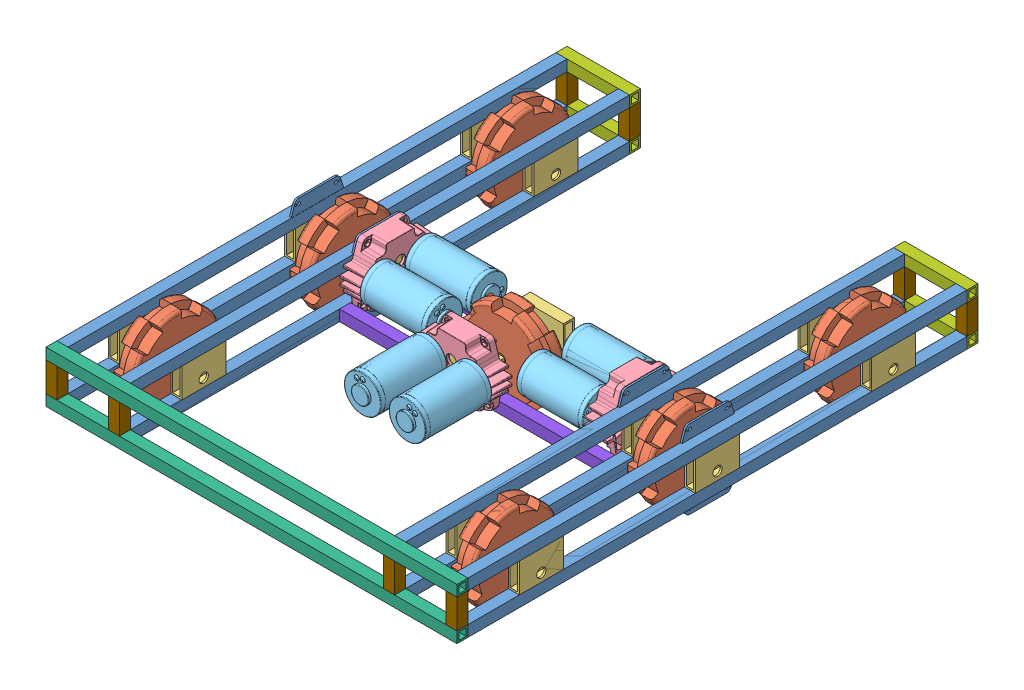
SolidWorks assembly Drive train Assem, configuration Default. Lengths in mm.
Overall size (711.2 207.75 901.7).
102 component instances, 9 part files, 40 mates.
Components (placement in the parent):
- Rod(38)-1: Rod(38) [Default] at (232.2427 460.842 1135.3317) size (19.05 42.61 863.6)
- Rod(38)-2: Rod(38) [Default] at (124.2927 460.842 1135.3317) size (19.05 42.61 863.6)
- Rod(38)-7: Rod(38) [Default] at (232.2427 390.992 271.7317) x (1 0 0) z (0 0 -1) size (19.05 42.61 863.6)
- Rod(38)-8: Rod(38) [Default] at (124.2927 390.992 271.7317) x (1 0 0) z (0 0 -1) size (19.05 42.61 863.6)
- Omni_Wheel_Six_Inch-1: Omni_Wheel_Six_Inch [Default] at (159.2177 414.8679 703.5318) x (1 0 0) z (0 0.491398 -0.870935) size (38.39 152.46 152.55)
- Wheel_Holder-1: Wheel_Holder [Default] at (232.2427 425.917 741.6317) size (19.05 50.8 76.2)
- Wheel_Holder-2: Wheel_Holder [Default] at (124.2927 425.917 665.4317) x (-1 0 0) z (0 0 -1) size (19.05 50.8 76.2)
- Wheel_Holder-5: Wheel_Holder [Default] at (124.2927 425.917 360.6317) x (-1 0 0) z (0 0 -1) size (19.05 50.8 76.2)
- Wheel_Holder-6: Wheel_Holder [Default] at (124.2927 425.917 970.2317) x (-1 0 0) z (0 0 -1) size (19.05 50.8 76.2)
- Wheel_Holder-7: Wheel_Holder [Default] at (124.2927 425.917 665.4317) x (-1 0 0) z (0 0 -1) size (19.05 50.8 76.2)
- Omni_Wheel_Six_Inch-3: Omni_Wheel_Six_Inch [Default] at (159.2177 414.8679 398.7318) x (1 0 0) z (0 0.491398 -0.870935) size (38.39 152.46 152.55)
- Omni_Wheel_Six_Inch-4: Omni_Wheel_Six_Inch [Default] at (159.2177 414.8679 1008.3318) x (1 0 0) z (0 0.491398 -0.870935) size (38.39 152.46 152.55)
- Omni_Wheel_Six_Inch-5: Omni_Wheel_Six_Inch [Default] at (159.2177 414.8679 703.5318) x (1 0 0) z (0 0.491398 -0.870935) size (38.39 152.46 152.55)
- Wheel_Holder-8: Wheel_Holder [Default] at (232.2427 425.917 436.8317) size (19.05 50.8 76.2)
- Wheel_Holder-9: Wheel_Holder [Default] at (232.2427 425.917 1046.4317) size (19.05 50.8 76.2)
- Wheel_Holder-10: Wheel_Holder [Default] at (232.2427 425.917 741.6317) size (19.05 50.8 76.2)
- TM_Housing-1: TM_Housing [Default] at (78.9537 414.868 703.5317) x (0 0 -1) z (1 0 0) size (139.9 118.55 41.53)
- CIM_Motor-1: CIM_Motor [Default] at (59.9037 530.8918 668.1595) x (0 0.376645 0.926357) z (1 0 0) size (64.01 64.01 154.94)
- CIM_Motor-2: CIM_Motor [Default] at (59.9037 328.3971 656.572) x (0 0.376645 -0.926357) z (1 0 0) size (64.01 64.01 154.94)
- Wheel_Holder-11: Wheel_Holder [Default] at (-459.9073 425.917 970.2317) x (-1 0 0) z (0 0 -1) size (19.05 50.8 76.2)
- Omni_Wheel_Six_Inch-6: Omni_Wheel_Six_Inch [Default] at (-425.2716 414.8679 703.5318) x (1 0 0) z (0 0.491398 -0.870935) size (38.39 152.46 152.55)
- Wheel_Holder-12: Wheel_Holder [Default] at (-351.9573 425.917 741.6317) size (19.05 50.8 76.2)
- Omni_Wheel_Six_Inch-7: Omni_Wheel_Six_Inch [Default] at (-425.2716 414.8679 703.5318) x (1 0 0) z (0 0.491398 -0.870935) size (38.39 152.46 152.55)
- Wheel_Holder-13: Wheel_Holder [Default] at (-351.9573 425.917 741.6317) size (19.05 50.8 76.2)
- TM_Housing-2: TM_Housing [Default] at (-306.6183 414.868 703.5317) x (0 0 1) z (-1 0 0) size (139.9 118.55 41.53)
- Omni_Wheel_Six_Inch-8: Omni_Wheel_Six_Inch [Default] at (-425.2716 414.8679 1008.3318) x (1 0 0) z (0 0.491398 -0.870935) size (38.39 152.46 152.55)
- Wheel_Holder-14: Wheel_Holder [Default] at (-351.9573 425.917 1046.4317) size (19.05 50.8 76.2)
- Wheel_Holder-15: Wheel_Holder [Default] at (-459.9073 425.917 360.6317) x (-1 0 0) z (0 0 -1) size (19.05 50.8 76.2)
- Omni_Wheel_Six_Inch-9: Omni_Wheel_Six_Inch [Default] at (-425.2716 414.8679 398.7318) x (1 0 0) z (0 0.491398 -0.870935) size (38.39 152.46 152.55)
- Wheel_Holder-16: Wheel_Holder [Default] at (-459.9073 425.917 665.4317) x (-1 0 0) z (0 0 -1) size (19.05 50.8 76.2)
- Rod(38)-9: Rod(38) [Default] at (-459.9073 460.842 271.7317) x (-1 0 0) z (0 0 -1) size (19.05 42.61 863.6)
- Rod(38)-10: Rod(38) [Default] at (-351.9573 390.992 1135.3317) x (-1 0 0) z (0 0 1) size (19.05 42.61 863.6)
- Rod(38)-11: Rod(38) [Default] at (-459.9073 390.992 1135.3317) x (-1 0 0) z (0 0 1) size (19.05 42.61 863.6)
- Rod(38)-12: Rod(38) [Default] at (-351.9573 460.842 271.7317) x (-1 0 0) z (0 0 -1) size (19.05 42.61 863.6)
- CIM_Motor-3: CIM_Motor [Default] at (-287.5683 328.3971 750.4913) x (0 0.376645 0.926357) z (-1 0 0) size (64.01 64.01 154.94)
- CIM_Motor-4: CIM_Motor [Default] at (-287.5683 530.8918 738.9039) x (0 0.376645 -0.926357) z (-1 0 0) size (64.01 64.01 154.94)
- Wheel_Holder-17: Wheel_Holder [Default] at (-351.9573 425.917 436.8317) size (19.05 50.8 76.2)
- Wheel_Holder-18: Wheel_Holder [Default] at (-459.9073 425.917 665.4317) x (-1 0 0) z (0 0 -1) size (19.05 50.8 76.2)
- Rod(28)-1: Rod(28) [Default] at (241.7677 460.842 1144.8567) x (0 0 -1) z (1 0 0) size (19.05 19.05 711.2)
- Rod(28)-2: Rod(28) [Default] at (-469.4323 390.992 1144.8567) x (0 0 -1) z (-1 0 0) size (19.05 19.05 711.2)
- Rod(5)-1: Rod(5) [Default] at (114.7677 460.842 262.2067) x (0 0 1) z (-1 0 0) size (19.05 19.05 127)
- Rod(5)-2: Rod(5) [Default] at (241.7677 390.992 262.2067) x (0 0 1) z (1 0 0) size (19.05 19.05 127)
- Rod(5)-3: Rod(5) [Default] at (-469.4323 460.842 262.2067) x (0 0 1) z (-1 0 0) size (19.05 19.05 127)
- Rod(5)-4: Rod(5) [Default] at (-342.4323 390.992 262.2067) x (0 0 1) z (1 0 0) size (19.05 19.05 127)
- Rod(18)-1: Rod(18) [Default] at (114.7677 390.992 643.2067) x (0 0 -1) z (1 0 0) size (19.05 19.05 457.2)
- Wheel_Holder-19: Wheel_Holder [Default] at (-151.9323 425.917 643.2067) x (0 0 1) z (-1 0 0) size (19.05 50.8 76.2)
- Wheel_Holder-20: Wheel_Holder [Default] at (-75.7323 425.917 763.8567) x (0 0 -1) z (1 0 0) size (19.05 50.8 76.2)
- Rod(18)-2: Rod(18) [Default] at (-342.4323 390.992 763.8567) x (0 0 1) z (-1 0 0) size (19.05 19.05 457.2)
- Omni_Wheel_Six_Inch-10: Omni_Wheel_Six_Inch [Default] at (-113.8323 414.868 722.5817) x (0 0 -1) z (0.155594 -0.987821 0) size (38.39 152.46 152.55)
- TM_Housing-3: TM_Housing [Default] at (-113.8323 414.868 809.1957) x (-0.99996 0.008991 0) z (0 0 -1) size (139.9 118.55 41.53)
- CIM_Motor-5: CIM_Motor [Default] at (-164.6523 370.9605 828.2457) x (-0.351705 0.936111 0) z (0 0 -1) size (64.01 64.01 154.94)
- CIM_Motor-6: CIM_Motor [Default] at (-180.7617 332.0262 828.2457) x (-0.844762 0.535142 0) z (0 0 -1) size (64.01 64.01 154.94)
- Rod(2)-1: Rod(2) [Default] at (124.2927 451.317 262.2067) x (1 0 0) z (0 1 0) size (19.05 19.05 50.8)
- Rod(2)-2: Rod(2) [Default] at (124.2927 400.517 1144.8567) x (1 0 0) z (0 -1 0) size (19.05 19.05 50.8)
- Rod(2)-3: Rod(2) [Default] at (232.2427 451.317 1144.8567) x (-1 0 0) z (0 1 0) size (19.05 19.05 50.8)
- Rod(2)-4: Rod(2) [Default] at (232.2427 400.517 262.2067) x (-1 0 0) z (0 -1 0) size (19.05 19.05 50.8)
- Rod(2)-5: Rod(2) [Default] at (-351.9573 400.517 262.2067) x (-1 0 0) z (0 -1 0) size (19.05 19.05 50.8)
- Wheel_Holder-21: Wheel_Holder [Default] at (-459.9073 425.917 970.2317) x (-1 0 0) z (0 0 -1) size (19.05 50.8 76.2)
- Omni_Wheel_Six_Inch-11: Omni_Wheel_Six_Inch [Default] at (-425.2716 414.8679 703.5318) x (1 0 0) z (0 0.491398 -0.870935) size (38.39 152.46 152.55)
- Wheel_Holder-22: Wheel_Holder [Default] at (-351.9573 425.917 741.6317) size (19.05 50.8 76.2)
- Omni_Wheel_Six_Inch-12: Omni_Wheel_Six_Inch [Default] at (-425.2716 414.8679 703.5318) x (1 0 0) z (0 0.491398 -0.870935) size (38.39 152.46 152.55)
- Wheel_Holder-23: Wheel_Holder [Default] at (-351.9573 425.917 741.6317) size (19.05 50.8 76.2)
- TM_Housing-4: TM_Housing [Default] at (-306.6183 414.868 703.5317) x (0 0 1) z (-1 0 0) size (139.9 118.55 41.53)
- Omni_Wheel_Six_Inch-13: Omni_Wheel_Six_Inch [Default] at (-425.2716 414.8679 1008.3318) x (1 0 0) z (0 0.491398 -0.870935) size (38.39 152.46 152.55)
- Wheel_Holder-24: Wheel_Holder [Default] at (-351.9573 425.917 1046.4317) size (19.05 50.8 76.2)
- Wheel_Holder-25: Wheel_Holder [Default] at (-459.9073 425.917 360.6317) x (-1 0 0) z (0 0 -1) size (19.05 50.8 76.2)
- Omni_Wheel_Six_Inch-14: Omni_Wheel_Six_Inch [Default] at (-425.2716 414.8679 398.7318) x (1 0 0) z (0 0.491398 -0.870935) size (38.39 152.46 152.55)
- Wheel_Holder-26: Wheel_Holder [Default] at (-459.9073 425.917 665.4317) x (-1 0 0) z (0 0 -1) size (19.05 50.8 76.2)
- Rod(38)-13: Rod(38) [Default] at (-459.9073 460.842 271.7317) x (-1 0 0) z (0 0 -1) size (19.05 42.61 863.6)
- Rod(38)-14: Rod(38) [Default] at (-351.9573 390.992 1135.3317) x (-1 0 0) z (0 0 1) size (19.05 42.61 863.6)
- Rod(38)-15: Rod(38) [Default] at (-459.9073 390.992 1135.3317) x (-1 0 0) z (0 0 1) size (19.05 42.61 863.6)
- Rod(38)-16: Rod(38) [Default] at (-351.9573 460.842 271.7317) x (-1 0 0) z (0 0 -1) size (19.05 42.61 863.6)
- CIM_Motor-7: CIM_Motor [Default] at (-287.5683 328.3971 750.4913) x (0 0.376645 0.926357) z (-1 0 0) size (64.01 64.01 154.94)
- CIM_Motor-8: CIM_Motor [Default] at (-287.5683 530.8918 738.9039) x (0 0.376645 -0.926357) z (-1 0 0) size (64.01 64.01 154.94)
- Wheel_Holder-27: Wheel_Holder [Default] at (-351.9573 425.917 436.8317) size (19.05 50.8 76.2)
- Wheel_Holder-28: Wheel_Holder [Default] at (-459.9073 425.917 665.4317) x (-1 0 0) z (0 0 -1) size (19.05 50.8 76.2)
- Rod(5)-5: Rod(5) [Default] at (-469.4323 460.842 262.2067) x (0 0 1) z (-1 0 0) size (19.05 19.05 127)
- Rod(2)-6: Rod(2) [Default] at (-351.9573 400.517 262.2067) x (-1 0 0) z (0 -1 0) size (19.05 19.05 50.8)
- Wheel_Holder-29: Wheel_Holder [Default] at (232.2427 425.917 1046.4317) size (19.05 50.8 76.2)
- Omni_Wheel_Six_Inch-15: Omni_Wheel_Six_Inch [Default] at (159.2177 414.8679 703.5318) x (1 0 0) z (0 0.491398 -0.870935) size (38.39 152.46 152.55)
- Wheel_Holder-30: Wheel_Holder [Default] at (124.2927 425.917 665.4317) x (-1 0 0) z (0 0 -1) size (19.05 50.8 76.2)
- Omni_Wheel_Six_Inch-16: Omni_Wheel_Six_Inch [Default] at (159.2177 414.8679 703.5318) x (1 0 0) z (0 0.491398 -0.870935) size (38.39 152.46 152.55)
- Wheel_Holder-31: Wheel_Holder [Default] at (124.2927 425.917 665.4317) x (-1 0 0) z (0 0 -1) size (19.05 50.8 76.2)
- TM_Housing-5: TM_Housing [Default] at (78.9537 414.868 703.5317) x (0 0 -1) z (1 0 0) size (139.9 118.55 41.53)
- Omni_Wheel_Six_Inch-17: Omni_Wheel_Six_Inch [Default] at (159.2177 414.8679 1008.3318) x (1 0 0) z (0 0.491398 -0.870935) size (38.39 152.46 152.55)
- Wheel_Holder-32: Wheel_Holder [Default] at (124.2927 425.917 970.2317) x (-1 0 0) z (0 0 -1) size (19.05 50.8 76.2)
- Wheel_Holder-33: Wheel_Holder [Default] at (232.2427 425.917 436.8317) size (19.05 50.8 76.2)
- Omni_Wheel_Six_Inch-18: Omni_Wheel_Six_Inch [Default] at (159.2177 414.8679 398.7318) x (1 0 0) z (0 0.491398 -0.870935) size (38.39 152.46 152.55)
- Wheel_Holder-34: Wheel_Holder [Default] at (232.2427 425.917 741.6317) size (19.05 50.8 76.2)
- Rod(38)-17: Rod(38) [Default] at (232.2427 460.842 1135.3317) size (19.05 42.61 863.6)
- Rod(38)-18: Rod(38) [Default] at (124.2927 390.992 271.7317) x (1 0 0) z (0 0 -1) size (19.05 42.61 863.6)
- Rod(38)-19: Rod(38) [Default] at (232.2427 390.992 271.7317) x (1 0 0) z (0 0 -1) size (19.05 42.61 863.6)
- Rod(38)-20: Rod(38) [Default] at (124.2927 460.842 1135.3317) size (19.05 42.61 863.6)
- CIM_Motor-9: CIM_Motor [Default] at (59.9037 530.8918 668.1595) x (0 0.376645 0.926357) z (1 0 0) size (64.01 64.01 154.94)
- CIM_Motor-10: CIM_Motor [Default] at (59.9037 328.3971 656.572) x (0 0.376645 -0.926357) z (1 0 0) size (64.01 64.01 154.94)
- Wheel_Holder-35: Wheel_Holder [Default] at (124.2927 425.917 360.6317) x (-1 0 0) z (0 0 -1) size (19.05 50.8 76.2)
- Wheel_Holder-36: Wheel_Holder [Default] at (232.2427 425.917 741.6317) size (19.05 50.8 76.2)
- Rod(5)-6: Rod(5) [Default] at (114.7677 460.842 262.2067) x (0 0 1) z (-1 0 0) size (19.05 19.05 127)
- Rod(2)-7: Rod(2) [Default] at (124.2927 451.317 262.2067) x (1 0 0) z (0 1 0) size (19.05 19.05 50.8)
- Rod(2)-8: Rod(2) [Default] at (-351.9573 451.317 1144.8567) x (-1 0 0) z (0 1 0) size (19.05 19.05 50.8)
- Rod(2)-9: Rod(2) [Default] at (-459.9073 400.517 1144.8567) x (1 0 0) z (0 -1 0) size (19.05 19.05 50.8)
- Rod(2)-10: Rod(2) [Default] at (-459.9073 451.317 262.2067) x (1 0 0) z (0 1 0) size (19.05 19.05 50.8)
Mates (geometry in assembly coordinates):
- Parallel1: parallel aligned: plane of Rod(38)-1 through (222.7177 470.367 271.7317) normal (0 1 0); plane of Rod(38)-2 through (114.7677 470.367 271.7317) normal (0 1 0)
- Parallel2: parallel aligned: plane of Rod(38)-1 through (241.7677 451.317 271.7317) normal (1 0 0); plane of Rod(38)-2 through (133.8177 451.317 271.7317) normal (1 0 0)
- Coincident3: coincident aligned: plane of Rod(38)-1 through (222.7177 451.317 271.7317) normal (0 -1 0); plane of Rod(38)-2 through (114.7677 451.317 271.7317) normal (0 -1 0)
- Coincident4: coincident aligned: plane of Rod(38)-1 through (232.2427 460.842 271.7317) normal (0 0 -1); plane of Rod(38)-2 through (124.2927 460.842 271.7317) normal (0 0 -1)
- Parallel3: parallel anti-aligned: plane of Rod(38)-1 through (222.7177 451.317 271.7317) normal (-1 0 0); plane of Omni_Wheel_Six_Inch-1 through (197.3177 414.8679 703.5318) normal (1 0 0)
- Distance3: distance = 88.9 mm anti-aligned: plane of Rod(38)-1 through (222.7177 451.317 271.7317) normal (-1 0 0); plane of Rod(38)-2 through (133.8177 451.317 271.7317) normal (1 0 0)
- Coincident9: coincident anti-aligned: plane of Omni_Wheel_Six_Inch-1 through (178.2677 414.8679 703.5318) normal (-1 0 0)
- Coincident10: coincident anti-aligned: plane of Rod(38)-7 through (222.7177 400.517 1135.3317) normal (0 1 0); plane of Wheel_Holder-1 through (222.7177 400.517 665.4317) normal (0 -1 0)
- Coincident12: coincident anti-aligned: plane of Rod(38)-7 through (222.7177 400.517 1135.3317) normal (0 1 0); plane of Wheel_Holder-1 through (222.7177 400.517 665.4317) normal (0 -1 0)
- Coincident13: coincident aligned: plane of Rod(38)-7 through (241.7677 400.517 1135.3317) normal (1 0 0); plane of Wheel_Holder-1 through (241.7677 400.517 665.4317) normal (1 0 0)
- Concentric1: concentric aligned: circle of Omni_Wheel_Six_Inch-1; circle of Wheel_Holder-1
- Symmetric1: symmetric aligned: plane of Wheel_Holder-1 through (232.2427 425.917 741.6317) normal (0 0 1); plane of Wheel_Holder-1 through (232.2427 425.917 665.4317) normal (0 0 -1)
- Coincident14: coincident anti-aligned: plane of Rod(38)-2 through (114.7677 451.317 271.7317) normal (-1 0 0); plane of TM_Housing-1 through (114.7677 414.868 703.5317) normal (1 0 0)
- Concentric2: concentric anti-aligned: cylinder of Wheel_Holder-7 through (133.8177 414.868 703.5317) axis (-1 0 0) radius 8.001; cylinder of TM_Housing-1 through (114.7677 414.868 703.5317) axis (1 0 0) radius 5.08
- Concentric3: concentric anti-aligned: cylinder of Rod(38)-2 through (117.9427 485.456 671.7817) axis (-1 0 0) radius 2.5576; cone of TM_Housing-1 through (109.416 485.456 671.7817) axis (1 0 0)
- Coincident15: coincident anti-aligned: plane of TM_Housing-1 through (78.9537 414.868 703.5317) normal (-1 0 0); plane of CIM_Motor-1 through (78.9537 443.038 742.2667) normal (1 0 0)
- Concentric4: concentric anti-aligned: cylinder of TM_Housing-1 through (114.7677 443.038 742.2667) axis (1 0 0) radius 10.414; cylinder of CIM_Motor-1 through (114.5177 443.038 742.2667) axis (-1 0 0) radius 4
- Coincident16: coincident anti-aligned: plane of Rod(38)-9 through (-459.9073 460.842 1135.3317) normal (0 0 1); plane of Rod(28)-1 through (-469.4323 451.317 1135.3317) normal (0 0 -1)
- Coincident17: coincident aligned: plane of Rod(38)-1 through (241.7677 451.317 271.7317) normal (1 0 0); plane of Rod(28)-1 through (241.7677 460.842 1144.8567) normal (1 0 0)
- Coincident18: coincident aligned: plane of Rod(38)-1 through (222.7177 451.317 271.7317) normal (0 -1 0); plane of Rod(28)-1 through (-469.4323 451.317 1154.3817) normal (0 -1 0)
- Coincident19: coincident anti-aligned: plane of Rod(38)-2 through (124.2927 460.842 271.7317) normal (0 0 -1); plane of Rod(5)-1 through (241.7677 451.317 271.7317) normal (0 0 1)
- Coincident20: coincident aligned: plane of Rod(38)-1 through (241.7677 451.317 271.7317) normal (1 0 0); plane of Rod(5)-1 through (241.7677 460.842 262.2067) normal (1 0 0)
- Coincident21: coincident aligned: plane of Rod(38)-2 through (114.7677 470.367 271.7317) normal (0 1 0); plane of Rod(5)-1 through (241.7677 470.367 252.6817) normal (0 1 0)
- Coincident22: coincident anti-aligned: plane of Rod(38)-10 through (-342.4323 400.517 271.7317) normal (1 0 0); plane of Rod(18)-1 through (-342.4323 390.992 643.2067) normal (-1 0 0)
- Coincident23: coincident aligned: plane of Rod(38)-10 through (-342.4323 400.517 271.7317) normal (0 1 0); plane of Rod(18)-1 through (-342.4323 400.517 652.7317) normal (0 1 0)
- Distance4: distance = 50.8 mm: plane of assembly through (0 0 703.5317) normal (0 0 1); plane of Rod(18)-1 through (-342.4323 381.467 652.7317) normal (0 0 1)
- Coincident24: coincident anti-aligned: plane of Rod(18)-1 through (-342.4323 400.517 652.7317) normal (0 1 0); plane of Wheel_Holder-19 through (-75.7323 400.517 633.6817) normal (0 -1 0)
- Coincident27: coincident aligned: plane of Rod(18)-1 through (-342.4323 381.467 652.7317) normal (0 0 1); plane of Wheel_Holder-19 through (-75.7323 400.517 652.7317) normal (0 0 1)
- Symmetric2: symmetric aligned: plane of Wheel_Holder-19 through (-75.7323 425.917 643.2067) normal (1 0 0); plane of Wheel_Holder-19 through (-151.9323 425.917 643.2067) normal (-1 0 0)
- Coincident28: coincident anti-aligned: plane of Omni_Wheel_Six_Inch-10 through (-113.8323 414.868 703.5317) normal (0 0 -1)
- Concentric5: concentric aligned: cylinder of Wheel_Holder-19 through (-113.8323 414.868 633.6817) axis (0 0 1) radius 8.001; cylinder of Omni_Wheel_Six_Inch-10 through (-113.8323 414.868 684.4817) axis (0 0 1) radius 7.9375
- Coincident30: coincident anti-aligned: plane of Wheel_Holder-20 through (-151.9323 400.517 773.3817) normal (0 0 1); plane of TM_Housing-3 through (-113.8323 414.868 773.3817) normal (0 0 -1)
- Concentric6: concentric aligned: cylinder of Wheel_Holder-20 through (-113.8323 414.868 773.3817) axis (0 0 -1) radius 8.001; cylinder of TM_Housing-3 through (-113.8323 414.868 773.3817) axis (0 0 -1) radius 5.08
- Coincident34: coincident anti-aligned: plane of TM_Housing-3 through (-113.8323 414.868 809.1957) normal (0 0 1); plane of CIM_Motor-5 through (-74.8456 442.6886 809.1957) normal (0 0 -1)
- Concentric7: concentric anti-aligned: cylinder of TM_Housing-3 through (-74.8456 442.6886 773.3817) axis (0 0 -1) radius 10.414; cylinder of CIM_Motor-5 through (-74.8456 442.6886 773.6317) axis (0 0 1) radius 4
- Coincident35: coincident anti-aligned: plane of TM_Housing-3 through (-113.8323 414.868 809.1957) normal (0 0 1); plane of CIM_Motor-6 through (-152.3124 443.3851 809.1957) normal (0 0 -1)
- Concentric8: concentric anti-aligned: cylinder of TM_Housing-3 through (-152.3124 443.3851 773.3817) axis (0 0 -1) radius 10.414; cylinder of CIM_Motor-6 through (-152.3124 443.3851 773.6317) axis (0 0 1) radius 4
- Coincident36: coincident anti-aligned: plane of Rod(5)-2 through (114.7677 400.517 252.6817) normal (0 1 0); plane of Rod(2)-1 through (124.2927 400.517 262.2067) normal (0 -1 0)
- Coincident37: coincident aligned: plane of Rod(5)-2 through (114.7677 400.517 252.6817) normal (0 0 -1); plane of Rod(2)-1 through (114.7677 400.517 252.6817) normal (0 0 -1)
- Coincident38: coincident aligned: plane of Rod(38)-8 through (114.7677 400.517 1135.3317) normal (-1 0 0); plane of Rod(2)-1 through (114.7677 400.517 271.7317) normal (-1 0 0)
